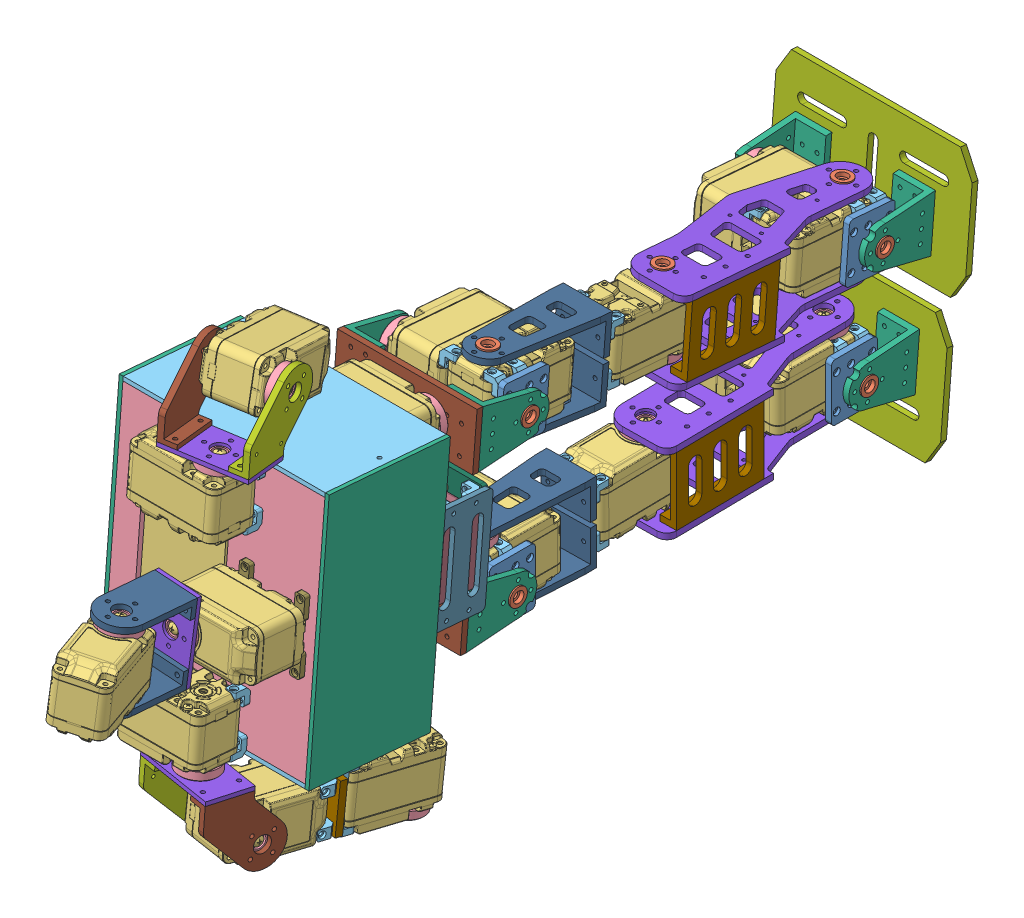
SolidWorks assembly Humanas (1), configuration Default. Lengths in mm.
Overall size (111.57 230.5 438.92).
186 component instances, 29 part files, 0 mates.
Components (placement in the parent):
- Bracket_1-1: Bracket_1 [Default] at (65.1733 -30.326 33.7891) x (0 0 1) z (0 1 0) size (23.4 3 29)
- support-1: support [Default] at (68.1733 -31.0515 31.398) x (1 0 0) z (0 0.680999 -0.732284) size (5.5 9 9)
- Herkulex-1: Herkulex [Default] at (14.7014 -30.8698 57.4255) x (0 -0.006981 -0.999976) z (0 -0.999976 0.006981) size (45.15 35.02 24.01)
- Herkulex horn-1: Herkulex horn [Default] at (15.1014 -13.8701 11.8463) x (0 -0.660105 0.751173) z (0 0.751173 0.660105) size (19.1 6.4 19)
- Herkulex-2: Herkulex [Default] at (49.9452 -22.026 57.4255) x (0.006981 0 -0.999976) z (-0.999976 0 -0.006981) size (45.15 35.02 24.01)
- Herkulex horn-2: Herkulex horn [Default] at (67.5795 -22.426 12.0881) x (-0.670529 0 0.741883) z (0.741883 0 0.670529) size (19.1 6.4 19)
- L joint-1: L joint [Default] at (37.9014 -18.826 61.1125) x (0 -1 0) z (-1 0 0) size (8.2 5.1 8.2)
- L joint-2: L joint [Default] at (37.9014 -42.8256 66.3382) x (0 1 0) z (-1 0 0) size (8.2 5.1 8.2)
- L joint-3: L joint [Default] at (38.1737 -42.226 27.2135) x (0 1 0) z (-1 0 0) size (8.2 5.1 8.2)
- L joint-4: L joint [Default] at (38.1737 -18.826 22.1135) x (0 -1 0) z (-1 0 0) size (8.2 5.1 8.2)
- L joint-5: L joint [Default] at (62.1733 -42.226 22.2391) x (0 1 0) z (1 0 0) size (8.2 5.1 8.2)
- L joint-6: L joint [Default] at (62.1733 -18.826 27.3391) x (0 -1 0) z (1 0 0) size (8.2 5.1 8.2)
- L joint-7: L joint [Default] at (62.0988 -18.826 38.0107) x (0 -1 0) z (1 0 0) size (8.2 5.1 8.2)
- L joint-8: L joint [Default] at (62.0988 -42.226 32.9107) x (0 1 0) z (1 0 0) size (8.2 5.1 8.2)
- support-2: support [Default] at (50.1269 -44.526 31.398) x (0 -1 0) z (-0.916251 0 -0.400604) size (5.5 9 9)
- 3D ankle support flange_1-1: 3D ankle support flange_1 [Default] at (72.9733 -31.0515 31.398) x (0 -0.99661 0.082269) z (0 -0.082269 -0.99661) size (28 18.5 35)
- 3D ankle support flange_1-2: 3D ankle support flange_1 [Default] at (1.5014 -31.0515 31.398) x (0 0.99661 -0.082269) z (0 -0.082269 -0.99661) size (28 18.5 35)
- foot_1-1: foot_1 [Default] at (37.0364 -40.6015 7.1013) x (0 -0.99661 0.082269) z (1 0 0) size (64 3 100)
- knee_1-1: knee_1 [Default] at (53.2497 -63.826 269.3775) x (0 1 0) z (0.999914 0 -0.013121) size (3 114 39.48)
- knee_1-2: knee_1 [Default] at (53.2497 -26.326 269.3775) x (0 1 0) z (0.999914 0 -0.013121) size (3 114 39.48)
- Knee bracket_1-1: Knee bracket_1 [Default] at (72.5652 -29.076 106.61) x (0 -1 0) z (-0.013121 0 -0.999914) size (34.5 8.5 45)
- support-3: support [Default] at (51.334 -44.526 123.39) x (0 -1 0) z (-0.185141 0 -0.982712) size (5.5 9 9)
- L joint-9: L joint [Default] at (45.3481 -42.226 158.7998) x (0 1 0) z (0.013121 0 0.999914) size (8.2 5.1 8.2)
- L joint-10: L joint [Default] at (58.247 -18.826 158.6305) x (0 -1 0) z (0.013121 0 0.999914) size (8.2 5.1 8.2)
- L joint-11: L joint [Default] at (40.2486 -18.826 158.8667) x (0 -1 0) z (0.013121 0 0.999914) size (8.2 5.1 8.2)
- L joint-12: L joint [Default] at (63.3466 -42.226 158.5636) x (0 1 0) z (0.013121 0 0.999914) size (8.2 5.1 8.2)
- upper leg_1-1: upper leg_1 [Default] at (53.1904 3.224 264.8555) x (0 -1 0) z (-0.999914 0 0.013121) size (19 60.48 25)
- upper leg_1-2: upper leg_1 [Default] at (53.1904 -64.276 264.8555) x (0 1 0) z (0.999914 0 -0.013121) size (19 60.48 25)
- Herkulex-3: Herkulex [Default] at (51.6756 -22.026 149.416) x (-0.013121 0 -0.999914) z (-0.999914 0 0.013121) size (45.15 35.02 24.01)
- Herkulex horn-3: Herkulex horn [Default] at (68.395 -22.426 103.7332) x (-0.65548 0 0.755212) z (0.755212 0 0.65548) size (19.1 6.4 19)
- support-4: support [Default] at (52.5081 -45.976 212.86) x (0 -1 0) z (0.88142 0 0.472334) size (5.5 9 9)
- L joint-13: L joint [Default] at (40.5091 -43.676 222.0831) x (0 1 0) z (-1 0 0.000107) size (8.2 5.1 8.2)
- Herkulex-4: Herkulex [Default] at (52.5053 -23.476 186.8318) x (0.000107 0 1) z (1 0 -0.000107) size (45.15 35.02 24.01)
- Herkulex horn-4: Herkulex horn [Default] at (35.1928 -23.876 232.2931) x (0.665254 0 -0.746617) z (-0.746617 0 -0.665254) size (19.1 6.4 19)
- Herkulex-5: Herkulex [Default] at (17.3053 -31.676 186.8356) x (0.000107 0 1) z (0 1 0) size (45.15 35.02 24.01)
- Herkulex horn-5: Herkulex horn [Default] at (17.7102 -48.9934 232.2949) x (-0.00008 0.665333 -0.746547) z (-0.000071 -0.746547 -0.665333) size (19.1 6.4 19)
- L joint-14: L joint [Default] at (40.5049 -43.676 183.0831) x (0 1 0) z (-1 0 0.000107) size (8.2 5.1 8.2)
- L joint-15: L joint [Default] at (40.5044 -20.276 177.9831) x (0 -1 0) z (-1 0 0.000107) size (8.2 5.1 8.2)
- L joint-16: L joint [Default] at (64.5091 -20.276 222.0805) x (0 -1 0) z (1 0 -0.000107) size (8.2 5.1 8.2)
- L joint-17: L joint [Default] at (64.5085 -43.676 216.9805) x (0 1 0) z (1 0 -0.000107) size (8.2 5.1 8.2)
- L joint-18: L joint [Default] at (64.5074 -43.676 206.3087) x (0 1 0) z (1 0 -0.000107) size (8.2 5.1 8.2)
- L joint-19: L joint [Default] at (64.5079 -20.276 211.4087) x (0 -1 0) z (1 0 -0.000107) size (8.2 5.1 8.2)
- Bracket_1-2: Bracket_1 [Default] at (67.5078 -32.176 210.5302) x (-0.000107 0 -1) z (0 -1 0) size (23.4 3 29)
- support-5: support [Default] at (70.5081 -32.276 212.8581) x (1 0 -0.000107) z (-0.000081 -0.646115 -0.76324) size (5.5 9 9)
- hip plate_1-1: hip plate_1 [Default] at (39.7101 46.314 231.4853) x (-0.000009 0.996638 -0.081927) z (1 0 -0.000107) size (28 3 71.2)
- 3D ankle support flange_1-3: 3D ankle support flange_1 [Default] at (75.3074 44.2658 206.5656) x (-0.000009 0.996638 -0.081927) z (0.000106 0.081927 0.996638) size (28 18.5 35)
- 3D ankle support flange_1-4: 3D ankle support flange_1 [Default] at (4.1074 44.2658 206.5732) x (0.000009 -0.996638 0.081927) z (0.000106 0.081927 0.996638) size (28 18.5 35)
- Herkulex-6: Herkulex [Default] at (17.3047 42.1334 180.6311) x (0.000106 0.081927 0.996638) z (-0.000009 0.996638 -0.081927) size (45.15 35.02 24.01)
- Herkulex horn-6: Herkulex horn [Default] at (17.7096 28.5986 227.3564) x (-0.000085 0.601934 -0.798546) z (-0.000064 -0.798546 -0.601934) size (19.1 6.4 19)
- Herkulex-7: Herkulex [Default] at (52.5047 33.961 181.2991) x (0.000106 0.081927 0.996638) z (-1 0 0.000107) size (45.15 35.02 24.01)
- Herkulex horn-7: Herkulex horn [Default] at (69.827 38.084 226.5711) x (-0.665412 -0.061162 -0.743966) z (0.746476 -0.054509 -0.663176) size (19.1 6.4 19)
- L joint-20: L joint [Default] at (40.5036 53.368 170.8252) x (0.000009 -0.996638 0.081927) z (-1 0 0.000107) size (8.2 5.1 8.2)
- L joint-21: L joint [Default] at (40.5078 56.5632 209.6941) x (0.000009 -0.996638 0.081927) z (-1 0 0.000107) size (8.2 5.1 8.2)
- L joint-22: L joint [Default] at (40.5085 33.0617 216.7432) x (-0.000009 0.996638 -0.081927) z (-1 0 0.000107) size (8.2 5.1 8.2)
- L joint-23: L joint [Default] at (40.5044 29.8665 177.8743) x (-0.000009 0.996638 -0.081927) z (-1 0 0.000107) size (8.2 5.1 8.2)
- Bracket_1-3: Bracket_1 [Default] at (67.5072 44.1748 204.2379) x (-0.000106 -0.081927 -0.996638) z (0.000009 -0.996638 0.081927) size (23.4 3 29)
- L joint-24: L joint [Default] at (64.5083 56.981 214.7744) x (0.000009 -0.996638 0.081927) z (1 0 -0.000107) size (8.2 5.1 8.2)
- L joint-25: L joint [Default] at (64.5072 56.1067 204.1385) x (0.000009 -0.996638 0.081927) z (1 0 -0.000107) size (8.2 5.1 8.2)
- L joint-26: L joint [Default] at (64.5068 32.3675 200.9727) x (-0.000009 0.996638 -0.081927) z (1 0 -0.000107) size (8.2 5.1 8.2)
- L joint-27: L joint [Default] at (64.508 33.2418 211.6087) x (-0.000009 0.996638 -0.081927) z (1 0 -0.000107) size (8.2 5.1 8.2)
- support-6: support [Default] at (70.5074 44.2658 206.5661) x (1 0 -0.000107) z (-0.000081 -0.646115 -0.76324) size (5.5 9 9)
- support-7: support [Default] at (52.5073 58.5178 205.3965) x (-0.000009 0.996638 -0.081927) z (0.574494 -0.067053 -0.815758) size (5.5 9 9)
- upper leg_1-3: upper leg_1 [Default] at (52.4861 81.0164 255.7224) x (0.000009 -0.996638 0.081927) z (-1 -0.000042 -0.000403) size (19 60.48 25)
- upper leg_1-4: upper leg_1 [Default] at (52.4867 13.7434 261.2525) x (-0.000009 0.996638 -0.081927) z (1 0.000042 0.000403) size (19 60.48 25)
- L joint-28: L joint [Default] at (58.9792 50.3443 151.7388) x (0.000009 -0.996638 0.081927) z (-0.000405 0.081927 0.996638) size (8.2 5.1 8.2)
- L joint-29: L joint [Default] at (40.9792 50.3436 151.7316) x (0.000009 -0.996638 0.081927) z (-0.000405 0.081927 0.996638) size (8.2 5.1 8.2)
- L joint-30: L joint [Default] at (46.0795 27.0225 153.6507) x (-0.000009 0.996638 -0.081927) z (-0.000405 0.081927 0.996638) size (8.2 5.1 8.2)
- L joint-31: L joint [Default] at (64.0794 27.0232 153.658) x (-0.000009 0.996638 -0.081927) z (-0.000405 0.081927 0.996638) size (8.2 5.1 8.2)
- Herkulex-8: Herkulex [Default] at (52.5332 29.4501 144.1224) x (0.000405 -0.081927 -0.996638) z (1 0.000042 0.000403) size (45.15 35.02 24.01)
- Herkulex horn-8: Herkulex horn [Default] at (35.2342 26.1236 98.7761) x (0.665031 0.06119 0.744305) z (-0.746816 0.054477 0.662796) size (19.1 6.4 19)
- support-8: support [Default] at (52.5435 49.742 116.3384) x (-0.000009 0.996638 -0.081927) z (0.279433 -0.078661 -0.956938) size (5.5 9 9)
- knee_1-3: knee_1 [Default] at (52.5581 49.046 262.8881) x (-0.000009 0.996638 -0.081927) z (1 0.000001 -0.0001) size (3 114 39.48)
- knee_1-4: knee_1 [Default] at (52.5584 11.6721 265.9603) x (-0.000009 0.996638 -0.081927) z (1 0.000001 -0.0001) size (3 114 39.48)
- Knee bracket_1-2: Knee bracket_1 [Default] at (73.9915 32.9922 101.1575) x (0.000009 -0.996638 0.081927) z (-0.000099 -0.081927 -0.996638) size (34.5 8.5 45)
- support-9: support [Default] at (52.5344 42.2048 24.6477) x (-0.000009 0.996638 -0.081927) z (0.998949 0.003764 0.045685) size (5.5 9 9)
- L joint-32: L joint [Default] at (40.5383 18.8506 61.5645) x (-0.000009 0.996638 -0.081927) z (-1 0 0.000107) size (8.2 5.1 8.2)
- L joint-33: L joint [Default] at (64.5337 15.8356 17.5611) x (-0.000009 0.996638 -0.081927) z (1 0 -0.000107) size (8.2 5.1 8.2)
- L joint-34: L joint [Default] at (40.5334 39.157 15.6466) x (0.000009 -0.996638 0.081927) z (-1 0 0.000107) size (8.2 5.1 8.2)
- L joint-35: L joint [Default] at (40.5342 16.2535 22.6465) x (-0.000009 0.996638 -0.081927) z (-1 0 0.000107) size (8.2 5.1 8.2)
- L joint-36: L joint [Default] at (40.5376 42.3521 54.5154) x (0.000009 -0.996638 0.081927) z (-1 0 0.000107) size (8.2 5.1 8.2)
- Herkulex-9: Herkulex [Default] at (17.3373 30.0852 51.7636) x (-0.000106 -0.081927 -0.996638) z (0.000009 -0.996638 0.081927) size (45.15 35.02 24.01)
- Herkulex horn-9: Herkulex horn [Default] at (17.7323 43.6201 5.0382) x (0.000085 -0.601934 0.798546) z (0.000064 0.798546 0.601934) size (19.1 6.4 19)
- L joint-37: L joint [Default] at (64.5351 40.4491 31.3628) x (0.000009 -0.996638 0.081927) z (1 0 -0.000107) size (8.2 5.1 8.2)
- L joint-38: L joint [Default] at (64.5348 16.7099 28.197) x (-0.000009 0.996638 -0.081927) z (1 0 -0.000107) size (8.2 5.1 8.2)
- L joint-39: L joint [Default] at (64.534 39.5748 20.7268) x (0.000009 -0.996638 0.081927) z (1 0 -0.000107) size (8.2 5.1 8.2)
- Bracket_1-4: Bracket_1 [Default] at (67.5348 28.6396 28.0689) x (0.000106 0.081927 0.996638) z (-0.000009 0.996638 -0.081927) size (23.4 3 29)
- support-10: support [Default] at (70.5345 28.5485 25.7401) x (1 0 -0.000107) z (-0.000074 0.718179 -0.695858) size (5.5 9 9)
- 3D ankle support flange_1-5: 3D ankle support flange_1 [Default] at (75.3345 28.5485 25.7395) x (0.000009 -0.996638 0.081927) z (-0.000106 -0.081927 -0.996638) size (28 18.5 35)
- 3D ankle support flange_1-6: 3D ankle support flange_1 [Default] at (4.1345 27.9528 25.8244) x (-0.000009 0.996638 -0.081927) z (-0.000106 -0.081927 -0.996638) size (28 18.5 35)
- foot_1-2: foot_1 [Default] at (43.1072 31.8936 -2.6264) x (-0.000009 0.996638 -0.081927) z (1 0 -0.000107) size (64 3 100)
- line loint-1: line loint [Default] at (20.186 -15.2328 270.0594) x (-0.000009 0.996638 -0.081927) z (1 0 -0.000107) size (11 2.6 5)
- line loint-2: line loint [Default] at (20.1835 -17.1499 246.7381) x (-0.000009 0.996638 -0.081927) z (-1 0 0.000107) size (11 2.6 5)
- line loint-3: line loint [Default] at (59.186 -15.2328 270.0553) x (-0.000009 0.996638 -0.081927) z (1 0 -0.000107) size (11 2.6 5)
- line loint-4: line loint [Default] at (59.1835 -17.1499 246.7339) x (-0.000009 0.996638 -0.081927) z (-1 0 0.000107) size (11 2.6 5)
- line loint-5: line loint [Default] at (20.1855 36.7917 265.7828) x (-0.000009 0.996638 -0.081927) z (1 0 -0.000107) size (11 2.6 5)
- line loint-6: line loint [Default] at (59.1855 36.7917 265.7787) x (-0.000009 0.996638 -0.081927) z (1 0 -0.000107) size (11 2.6 5)
- line loint-7: line loint [Default] at (20.1831 34.8746 242.4615) x (-0.000009 0.996638 -0.081927) z (-1 0 0.000107) size (11 2.6 5)
- line loint-8: line loint [Default] at (59.1831 34.8746 242.4573) x (-0.000009 0.996638 -0.081927) z (-1 0 0.000107) size (11 2.6 5)
- lipo_1-1: lipo_1 [Default] at (33.683 8.6494 242.0071) x (-0.000009 0.996638 -0.081927) z (1 0 -0.000107) size (33 24 103)
- L joint-40: L joint [Default] at (82.1854 -9.8531 264.092) x (-1 0 0.000107) z (0.000106 0.081927 0.996638) size (8.2 5.1 8.2)
- L joint-41: L joint [Default] at (82.185 35.5936 260.3562) x (-1 0 0.000107) z (0.000106 0.081927 0.996638) size (8.2 5.1 8.2)
- L joint-42: L joint [Default] at (82.1836 -16.3697 247.0687) x (-1 0 0.000107) z (-0.000106 -0.081927 -0.996638) size (8.2 5.1 8.2)
- L joint-43: L joint [Default] at (82.1832 29.0771 243.3328) x (-1 0 0.000107) z (-0.000106 -0.081927 -0.996638) size (8.2 5.1 8.2)
- battery support_1-1: battery support_1 [Default] at (87.6845 9.8209 256.2533) x (-0.000009 0.996638 -0.081927) z (0.000106 0.081927 0.996638) size (52.2 2.5 28.5)
- hip plate 2_1-1: hip plate 2_1 [Default] at (39.9869 -1.8314 259.0612) x (0.000009 -0.996638 0.081927) z (-1 0 0.000107) size (52.2 2.5 93.44)
- hip plate 2_1-2: hip plate 2_1 [Default] at (39.9841 -3.9615 233.1486) x (0.000009 -0.996638 0.081927) z (-1 0 0.000107) size (52.2 2.5 93.44)
- Fitpc_1-1: Fitpc_1 [Default] at (39.7145 11.1973 273.0019) x (-0.000009 0.996638 -0.081927) z (1 0 -0.000107) size (115 27.5 101)
- line loint-9: line loint [Default] at (48.5135 61.309 263.7644) x (-0.000009 0.996638 -0.081927) z (1 0 -0.000107) size (11 2.6 5)
- line loint-10: line loint [Default] at (48.5144 -39.7501 272.0718) x (-0.000009 0.996638 -0.081927) z (1 0 -0.000107) size (11 2.6 5)
- line loint-11: line loint [Default] at (20.1862 -39.7501 272.0748) x (-0.000009 0.996638 -0.081927) z (1 0 -0.000107) size (11 2.6 5)
- line loint-12: line loint [Default] at (20.1853 61.309 263.7674) x (-0.000009 0.996638 -0.081927) z (1 0 -0.000107) size (11 2.6 5)
- line loint-13: line loint [Default] at (59.1853 61.309 263.7633) x (-0.000009 0.996638 -0.081927) z (1 0 -0.000107) size (11 2.6 5)
- line loint-14: line loint [Default] at (59.1862 -39.7501 272.0707) x (-0.000009 0.996638 -0.081927) z (1 0 -0.000107) size (11 2.6 5)
- Fitpc base_1-1: Fitpc base_1 [Default] at (40.2447 10.9925 270.5103) x (-0.000009 0.996638 -0.081927) z (1 0 -0.000107) size (122 2.5 103)
- Herkulex-10: Herkulex [Default] at (52.5374 21.9128 52.4317) x (-0.000106 -0.081927 -0.996638) z (1 0 -0.000107) size (45.15 35.02 24.01)
- Herkulex horn-10: Herkulex horn [Default] at (35.2151 18.5871 7.0942) x (0.665412 0.061162 0.743966) z (-0.746476 0.054509 0.663176) size (19.1 6.4 19)
- Herkulex-11: Herkulex [Default] at (26.484 -29.1464 250.9344) x (1 0 -0.000107) z (0.000009 -0.996638 0.081927) size (45.15 35.02 24.01)
- Herkulex horn-11: Herkulex horn [Default] at (71.9433 -11.8544 249.9094) x (-0.746541 -0.663097 0.054588) z (-0.66534 0.744037 -0.061091) size (19.1 6.4 19)
- Herkulex-12: Herkulex [Default] at (26.4833 47.3954 244.6424) x (1 0 -0.000107) z (0.000009 -0.996638 0.081927) size (45.15 35.02 24.01)
- Herkulex horn-12: Herkulex horn [Default] at (71.9426 64.6874 243.6174) x (-0.746541 -0.663097 0.054588) z (-0.66534 0.744037 -0.061091) size (19.1 6.4 19)
- 3D ankle support flange_1-7: 3D ankle support flange_1 [Default] at (4.1081 -31.676 212.8651) x (0.000009 -0.996638 0.081927) z (0.000106 0.081927 0.996638) size (28 18.5 35)
- 3D ankle support flange_1-8: 3D ankle support flange_1 [Default] at (75.3081 -32.276 212.8576) x (-0.000009 0.996638 -0.081927) z (0.000106 0.081927 0.996638) size (28 18.5 35)
- hip plate_1-2: hip plate_1 [Default] at (39.7107 -30.2278 237.7773) x (-0.000009 0.996638 -0.081927) z (1 0 -0.000107) size (28 3 71.2)
- Custom PCB-1: Custom PCB [Default] at (40.2181 13.9418 306.3892) x (1 0 -0.000107) z (0.000009 -0.996638 0.081927) size (100 1.7 115)
- TM4c-1: TM4c [Default] at (26.5393 24.4525 317.808) x (0.000009 -0.996638 0.081927) z (-1 0 0.000107) size (50.8 17.5 66.04)
- male_header_pin-1: male_header_pin [Default] at (44.4902 44.5765 308.9094) x (-0.000009 0.996638 -0.081927) z (-1 0 0.000107) size (2.54 11.54 30)
- male_header_pin-2: male_header_pin [Default] at (44.4906 2.1433 312.3976) x (-0.000009 0.996638 -0.081927) z (-1 0 0.000107) size (2.54 11.54 30)
- male_header_pin-3: male_header_pin [Default] at (44.4902 47.109 308.7012) x (-0.000009 0.996638 -0.081927) z (-1 0 0.000107) size (2.54 11.54 30)
- male_header_pin-4: male_header_pin [Default] at (44.4905 4.6757 312.1894) x (-0.000009 0.996638 -0.081927) z (-1 0 0.000107) size (2.54 11.54 30)
- Sensorhub-1: Sensorhub [Default] at (23.5223 25.3783 329.0703) x (-0.000009 0.996638 -0.081927) z (1 0 -0.000107) size (50.8 10.3 40.64)
- Fitpc Top-1: Fitpc Top [Default] at (40.251 15.8704 329.8501) x (-0.000009 0.996638 -0.081927) z (1 0 -0.000107) size (122 2.5 103)
- L joint-44: L joint [Default] at (85.1682 -44.109 308.1463) x (-0.000106 -0.081927 -0.996638) z (0.000009 -0.996638 0.081927) size (8.2 5.1 8.2)
- L joint-45: L joint [Default] at (-4.7318 -44.109 308.1559) x (-0.000009 0.996638 -0.081927) z (0.000106 0.081927 0.996638) size (8.2 5.1 8.2)
- L joint-46: L joint [Default] at (85.1672 71.5011 298.6428) x (0.000009 -0.996638 0.081927) z (0.000106 0.081927 0.996638) size (8.2 5.1 8.2)
- L joint-47: L joint [Default] at (-9.8328 71.5011 298.6529) x (0.000009 -0.996638 0.081927) z (0.000106 0.081927 0.996638) size (8.2 5.1 8.2)
- Fitpc side plate-1: Fitpc side plate [Default] at (40.2474 74.3288 296.4284) x (1 0 -0.000107) z (0.000106 0.081927 0.996638) size (103 2 62.04)
- Fitpc side plate-2: Fitpc side plate [Default] at (40.2485 -49.2544 306.5874) x (1 0 -0.000107) z (0.000106 0.081927 0.996638) size (103 2 62.04)
- Fitpc front-1: Fitpc front [Default] at (93.7479 13.5338 301.4203) x (-0.000009 0.996638 -0.081927) z (0.000106 0.081927 0.996638) size (126 2 62.04)
- Fitpc front-2: Fitpc front [Default] at (-11.2521 13.5338 301.4315) x (-0.000009 0.996638 -0.081927) z (0.000106 0.081927 0.996638) size (126 2 62.04)
- Herkulex-13: Herkulex [Default] at (26.5033 -39.305 351.9462) x (1 0 -0.000107) z (0.000106 0.081927 0.996638) size (45.15 35.02 24.01)
- Herkulex horn-13: Herkulex horn [Default] at (71.9609 -40.3251 334.6494) x (-0.746476 0.054509 0.663176) z (-0.665412 -0.061162 -0.743966) size (19.1 6.4 19)
- L joint-48: L joint [Default] at (56.6521 -43.4773 340.2455) x (-0.000009 0.996638 -0.081927) z (-0.000106 -0.081927 -0.996638) size (8.2 5.1 8.2)
- L joint-49: L joint [Default] at (17.6521 -43.4773 340.2496) x (-0.000009 0.996638 -0.081927) z (-0.000106 -0.081927 -0.996638) size (8.2 5.1 8.2)
- L joint-50: L joint [Default] at (61.7519 -20.156 338.3278) x (0.000009 -0.996638 0.081927) z (-0.000106 -0.081927 -0.996638) size (8.2 5.1 8.2)
- L joint-51: L joint [Default] at (22.7519 -20.156 338.332) x (0.000009 -0.996638 0.081927) z (-0.000106 -0.081927 -0.996638) size (8.2 5.1 8.2)
- Herkulex-14: Herkulex [Default] at (26.5023 73.9132 342.6393) x (1 0 -0.000107) z (-0.000106 -0.081927 -0.996638) size (45.15 35.02 24.01)
- Herkulex horn-14: Herkulex horn [Default] at (71.9636 74.9333 359.9264) x (-0.746617 -0.054509 -0.663017) z (-0.665254 0.061162 0.744108) size (19.1 6.4 19)
- L joint-52: L joint [Default] at (61.751 76.1193 330.4137) x (0.000009 -0.996638 0.081927) z (-0.000106 -0.081927 -0.996638) size (8.2 5.1 8.2)
- L joint-53: L joint [Default] at (22.751 76.1193 330.4179) x (0.000009 -0.996638 0.081927) z (-0.000106 -0.081927 -0.996638) size (8.2 5.1 8.2)
- L joint-54: L joint [Default] at (17.6512 52.7979 332.3355) x (-0.000009 0.996638 -0.081927) z (-0.000106 -0.081927 -0.996638) size (8.2 5.1 8.2)
- L joint-55: L joint [Default] at (56.6512 52.7979 332.3313) x (-0.000009 0.996638 -0.081927) z (-0.000106 -0.081927 -0.996638) size (8.2 5.1 8.2)
- Herkulex-15: Herkulex [Default] at (78.9137 17.9431 355.0609) x (-1 0 0.000107) z (0.000009 -0.996638 0.081927) size (45.15 35.02 24.01)
- Herkulex horn-15: Herkulex horn [Default] at (33.454 35.1696 353.2484) x (0.746552 -0.663097 0.054429) z (0.665327 0.744037 -0.061233) size (19.1 6.4 19)
- Herkulex-16: Herkulex [Default] at (66.7119 -79.8278 314.9621) x (-0.172133 0.107764 0.979162) z (-0.004672 -0.994076 0.108584) size (45.15 35.02 24.01)
- Herkulex horn-16: Herkulex horn [Default] at (58.5738 -57.7198 357.5251) x (0.125396 -0.741842 -0.658745) z (0.118013 0.670426 -0.732531) size (19.1 6.4 19)
- support-11: support [Default] at (40.0677 -77.3406 336.5865) x (-0.985063 -0.014116 -0.171616) z (-0.135359 -0.552573 0.822399) size (5.5 9 9)
- shoulder_1-1: shoulder_1 [Default] at (-25.9028 -82.3199 346.8151) x (0.985063 0.014116 0.171616) z (0.172196 -0.080702 -0.981751) size (9 35.45 38)
- shoulder plaate_1-1: shoulder plaate_1 [Default] at (52.5316 -49.4707 352.7791) x (0.985063 0.014116 0.171616) z (0.172196 -0.080702 -0.981751) size (40.5 2 22)
- line loint-15: line loint [Default] at (85.2111 28.3338 331.3292) x (-0.000009 0.996638 -0.081927) z (1 0 -0.000107) size (11 2.6 5)
- line loint-16: line loint [Default] at (85.2113 3.8165 333.3446) x (-0.000009 0.996638 -0.081927) z (1 0 -0.000107) size (11 2.6 5)
- line loint-17: line loint [Default] at (56.883 28.3338 331.3322) x (-0.000009 0.996638 -0.081927) z (1 0 -0.000107) size (11 2.6 5)
- line loint-18: line loint [Default] at (56.8832 3.8165 333.3476) x (-0.000009 0.996638 -0.081927) z (1 0 -0.000107) size (11 2.6 5)
- shoulder plaate_1-2: shoulder plaate_1 [Default] at (52.5304 86.0721 341.637) x (0.984532 -0.014345 -0.174617) z (-0.175205 -0.080661 -0.981222) size (40.5 2 22)
- shoulder_1-2: shoulder_1 [Default] at (130.9381 115.4936 330.3138) x (-0.984532 0.014345 0.174617) z (-0.175205 -0.080661 -0.981222) size (9 35.45 38)
- Herkulex-17: Herkulex [Default] at (52.1466 103.5806 297.6607) x (0.173705 0.210046 0.962137) z (0.022875 -0.977586 0.209288) size (45.15 35.02 24.01)
- Herkulex horn-17: Herkulex horn [Default] at (59.2532 130.0642 337.8444) x (-0.114459 -0.807229 -0.579033) z (-0.132649 0.590064 -0.796385) size (19.1 6.4 19)
- support-12: support [Default] at (34.5159 109.3705 326.6322) x (-0.984532 0.014345 0.174617) z (0.137735 -0.552605 0.821983) size (5.5 9 9)
- L joint-56: L joint [Default] at (71.411 -92.2665 307.6592) x (-0.985063 -0.014116 -0.171616) z (0.172133 -0.107764 -0.979162) size (8.2 5.1 8.2)
- L joint-57: L joint [Default] at (71.4951 -74.3731 305.7047) x (-0.985063 -0.014116 -0.171616) z (0.172133 -0.107764 -0.979162) size (8.2 5.1 8.2)
- L joint-58: L joint [Default] at (48.3844 -87.527 303.0896) x (0.985063 0.014116 0.171616) z (0.172133 -0.107764 -0.979162) size (8.2 5.1 8.2)
- L joint-59: L joint [Default] at (48.4685 -69.6336 301.1351) x (0.985063 0.014116 0.171616) z (0.172133 -0.107764 -0.979162) size (8.2 5.1 8.2)
- arm plate-1: arm plate [Default] at (60.234 -82.0876 298.14) x (-0.985063 -0.014116 -0.171616) z (0.004672 0.994076 -0.108584) size (29.4 3.3 24.1)
- L joint-60: L joint [Default] at (49.8115 -94.0484 294.5603) x (0.172133 -0.107764 -0.979162) z (-0.004672 -0.994076 0.108584) size (8.2 5.1 8.2)
- L joint-61: L joint [Default] at (67.5426 -93.7943 297.6494) x (0.172133 -0.107764 -0.979162) z (-0.004672 -0.994076 0.108584) size (8.2 5.1 8.2)
- L joint-62: L joint [Default] at (72.6786 -69.8645 295.9186) x (0.172133 -0.107764 -0.979162) z (0.004672 0.994076 -0.108584) size (8.2 5.1 8.2)
- L joint-63: L joint [Default] at (54.9447 -70.715 292.8947) x (0.172133 -0.107764 -0.979162) z (0.004672 0.994076 -0.108584) size (8.2 5.1 8.2)
- Herkulex-18: Herkulex [Default] at (62.8048 -91.7065 287.0888) x (0.172133 -0.107764 -0.979162) z (0.985063 0.014116 0.171616) size (45.15 35.02 24.01)
- Herkulex horn-18: Herkulex horn [Default] at (53.573 -96.4522 239.5613) x (0.52689 0.089842 0.845172) z (-0.849921 0.06116 0.523349) size (19.1 6.4 19)
- shoulder plaate_1-3: shoulder plaate_1 [Default] at (52.8868 18.9426 367.2227) x (0.06291 0.994664 -0.081771) z (-0.998019 0.062708 -0.005048) size (40.5 2 22)
- head side plate-1: head side plate [Default] at (51.6143 -0.0523 382.8315) x (0.000106 0.081927 0.996638) z (-0.998019 0.062708 -0.005048) size (39 9 22)
- shoulder2_1-1: shoulder2_1 [Default] at (11.0371 -81.7905 353.2507) x (0.985063 0.014116 0.171616) z (0.172196 -0.080702 -0.981751) size (9 35.45 38)
- shoulder2_1-2: shoulder2_1 [Default] at (94.0181 116.0315 336.8619) x (-0.984532 0.014345 0.174617) z (-0.175205 -0.080661 -0.981222) size (9 35.45 38)
- head side plate-2: head side plate [Default] at (54.1622 40.2315 379.5198) x (0.000106 0.081927 0.996638) z (0.998019 -0.062708 0.005048) size (39 9 22)
- Herkulex-19: Herkulex [Default] at (62.7799 29.6421 418.7654) x (-0.362937 -0.053523 -0.930275) z (-0.929687 0.088202 0.357633) size (45.15 35.02 24.01)
- Herkulex horn-19: Herkulex horn [Default] at (62.3556 25.2837 370.3151) x (-0.347602 0.098641 0.932439) z (0.935529 -0.030236 0.351953) size (19.1 6.4 19)
- support-13: support [Default] at (51.9178 5.869 396.3919) x (-0.06291 -0.994664 0.081771) z (0.994559 -0.069298 -0.07778) size (5.5 9 9)
